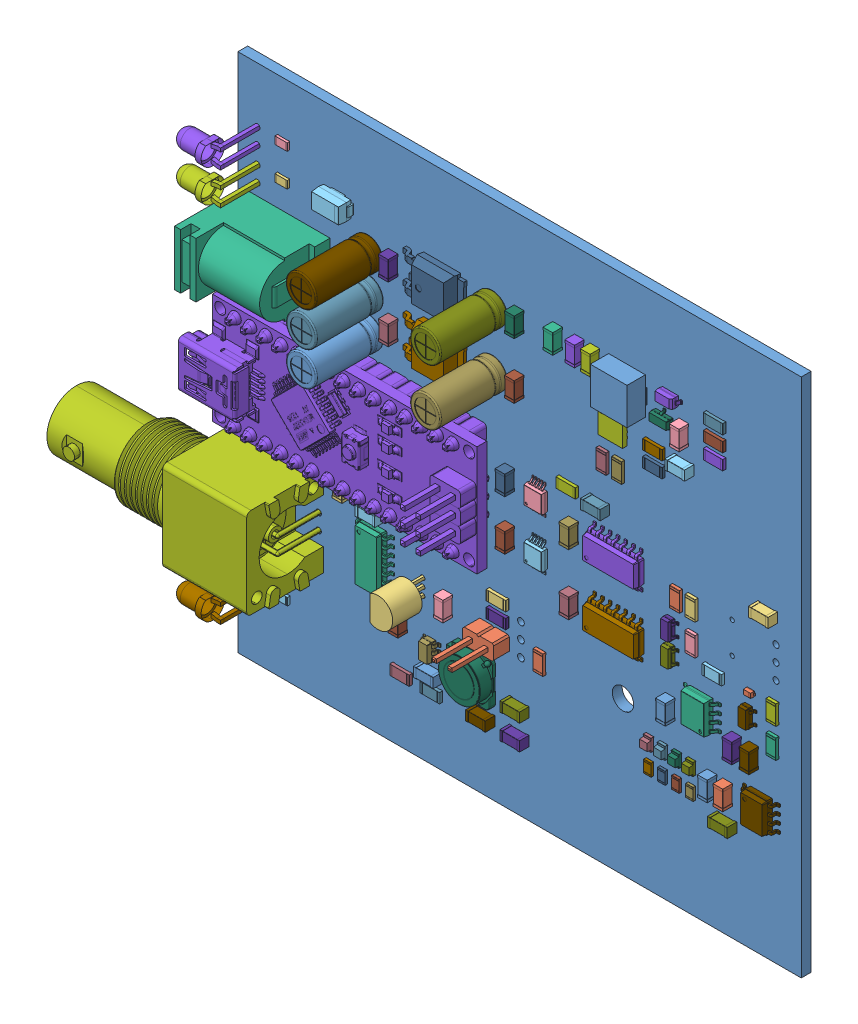
SolidWorks assembly PCBA_cut, configuration Domyślna. Lengths in mm.
Overall size (111.73 85 18.8).
103 component instances, 99 part files, 0 mates.
Components (placement in the parent):
- PCBA.step-1: PCBA.step [Domyślna] at origin size (111.73 89 18.8)
  - Board_Geoms_e78a.step-1: Board_Geoms_e78a.step [Domyślna] at origin size (92 89 1.6)
    - Pcb_e78a.step-1: Pcb_e78a.step [Domyślna] at (-104.194 136.428 0) size (92 89 1.6)
    - PCB_Sketch_e78a.step-1: PCB_Sketch_e78a.step [Domyślna] at origin (suppressed, hidden)
  - Step_Models_e78a.step-1: Step_Models_e78a.step [Domyślna] at origin size (108.33 68.14 18.8)
    - Top_e78a.step-1: Top_e78a.step [Domyślna] at origin size (108.33 68.14 18.8)
      - R28_R_1206_3216Metric_60135E3C.step-1: R28_R_1206_3216Metric_60135E3C.step [Domyślna] at (49.53 8.636 0) x (0 1 0) z (0 0 1) size (3.2 1.6 0.55)
      - R27_R_0805_2012Metric_5F3C1C00.step-1: R27_R_0805_2012Metric_5F3C1C00.step [Domyślna] at (7.493 55.626 0) size (2 1.2 0.45)
      - R26_R_0805_2012Metric_5F3C1C30.step-1: R26_R_0805_2012Metric_5F3C1C30.step [Domyślna] at (7.493 60.96 0) size (2 1.2 0.45)
      - R25_R_0805_2012Metric_5F3C1E7C.step-1: R25_R_0805_2012Metric_5F3C1E7C.step [Domyślna] at (7.5415 -3.302 0) size (2 1.2 0.45)
      - R24_R_0805_2012Metric_60130AB3.step-1: R24_R_0805_2012Metric_60130AB3.step [Domyślna] at (7.493 2.032 0) size (2 1.2 0.45)
      - D12_LED_D3.0mm_Horizontal_O1.27mm_Z6.0mm_5F3C2200.step-1: D12_LED_D3.0mm_Horizontal_O1.27mm_Z6.0mm_5F3C2200.step [Domyślna] at (3.175 55.626 0) x (0 -1 0) z (0 0 1) size (3.48 6.88 9.91)
      - D11_LED_D3.0mm_Horizontal_O1.27mm_Z6.0mm_5F3C2185.step-1: D11_LED_D3.0mm_Horizontal_O1.27mm_Z6.0mm_5F3C2185.step [Domyślna] at (3.175 60.96 0) x (0 -1 0) z (0 0 1) size (3.48 6.88 9.91)
      - D10_LED_D3.0mm_Horizontal_O1.27mm_Z6.0mm_5F3C56BC.step-1: D10_LED_D3.0mm_Horizontal_O1.27mm_Z6.0mm_5F3C56BC.step [Domyślna] at (3.175 -3.302 0) x (0 -1 0) z (0 0 1) size (3.48 6.88 9.91)
      - D9_LED_D3.0mm_Horizontal_O1.27mm_Z6.0mm_5F3C1D9F.step-1: D9_LED_D3.0mm_Horizontal_O1.27mm_Z6.0mm_5F3C1D9F.step [Domyślna] at (3.175 2.032 0) x (0 -1 0) z (0 0 1) size (3.48 6.88 9.91)
      - C31_C_1206_3216Metric_5F0E55A1.step-1: C31_C_1206_3216Metric_5F0E55A1.step [Domyślna] at (26.924 3.302 0) x (0 -1 0) z (0 0 1) size (3.2 1.6 1.6)
      - IC12_SOT_23_6_5F31C27B.step-1: IC12_SOT_23_6_5F31C27B.step [Domyślna] at (31.75 1.651 0) x (-1 0 0) z (0 0 1) size (2.8 2.9 1.55)
      - R23_R_1206_3216Metric_5F31C265.step-1: R23_R_1206_3216Metric_5F31C265.step [Domyślna] at (26.924 -4.445 0) size (3.2 1.6 0.55)
      - R22_R_1206_3216Metric_5F31DD4A.step-1: R22_R_1206_3216Metric_5F31DD4A.step [Domyślna] at (31.877 -4.445 0) x (-1 0 0) z (0 0 1) size (3.2 1.6 0.55)
      - L2_Sf_fd_sp_5F31CDB4[2].step-1: L2_Sf_fd_sp_5F31CDB4[2].step [Domyślna] at (38.608 1.651 0.0508) size (7 7 2.5)
      - C36_C_1206_3216Metric_5F31B990.step-1: C36_C_1206_3216Metric_5F31B990.step [Domyślna] at (45.974 0.381 0) size (3.2 1.6 1.6)
      - C35_C_1206_3216Metric_5F31B97F.step-1: C35_C_1206_3216Metric_5F31B97F.step [Domyślna] at (45.974 -3.683 0) size (3.2 1.6 1.6)
      - C34_C_1206_3216Metric_5F31B96E.step-1: C34_C_1206_3216Metric_5F31B96E.step [Domyślna] at (40.386 -3.683 0) x (-1 0 0) z (0 0 1) size (3.2 1.6 1.6)
      - C33_C_1206_3216Metric_5F31B95D.step-1: C33_C_1206_3216Metric_5F31B95D.step [Domyślna] at (31.877 -1.778 0) x (-1 0 0) z (0 0 1) size (3.2 1.6 1.6)
      - C32_C_1206_3216Metric_5F2DB7B1.step-1: C32_C_1206_3216Metric_5F2DB7B1.step [Domyślna] at (5.334 24.384 0) x (-1 0 0) z (0 0 1) size (3.2 1.6 1.6)
      - R21_R_1206_3216Metric_5F2CE966.step-1: R21_R_1206_3216Metric_5F2CE966.step [Domyślna] at (42.672 13.97 0) size (3.2 1.6 0.55)
      - IC8_DS1124U-25+_5F0C9A39.step-1: IC8_DS1124U-25+_5F0C9A39.step [Domyślna] at (49.222 31.78 0) x (0 1 0) z (0 0 1) size (4.9 3 1.1)
      - IC7_DS1124U-25+_5F0C50CD.step-1: IC7_DS1124U-25+_5F0C50CD.step [Domyślna] at (49.222 23.652 0) x (0 1 0) z (0 0 1) size (4.9 3 1.1)
      - IC2_TLV3501AIDR_5F0DC31C.step-1: IC2_TLV3501AIDR_5F0DC31C.step [Domyślna] at (75.944 15.19 0) x (-1 0 0) z (0 0 1) size (6 4.9 1.75)
      - IC1_MAX1932ETC+_5F0DC301.step-1: IC1_MAX1932ETC+_5F0DC301.step [Domyślna] at (61.614 48.076 0) size (4.1 4.1 0.8)
      - D1_BAT46W-E3-08_5F0B6668.step-1: D1_BAT46W-E3-08_5F0B6668.step [Domyślna] at (70.758 56.712 0) x (-1 0 0) z (0 0 1) size (3.7 1.55 1.35)
      - R20_R_0805_2012Metric_5F2C1AB9.step-1: R20_R_0805_2012Metric_5F2C1AB9.step [Domyślna] at (67.31 2.54 0) x (0 -1 0) z (0 0 1) size (2 1.2 0.45)
      - R19_R_0805_2012Metric_5F2C1B19.step-1: R19_R_0805_2012Metric_5F2C1B19.step [Domyślna] at (69.596 2.54 0) x (0 -1 0) z (0 0 1) size (2 1.2 0.45)
      - R16_R_0805_2012Metric_5F2C1B49.step-1: R16_R_0805_2012Metric_5F2C1B49.step [Domyślna] at (71.882 2.54 0) x (0 -1 0) z (0 0 1) size (2 1.2 0.45)
      - R13_R_0805_2012Metric_5F2C1AE9.step-1: R13_R_0805_2012Metric_5F2C1AE9.step [Domyślna] at (74.168 2.54 0) x (0 -1 0) z (0 0 1) size (2 1.2 0.45)
      - D8_LED_0805_2012Metric_5F2C1BB1.step-1: D8_LED_0805_2012Metric_5F2C1BB1.step [Domyślna] at (67.31 6.096 0) x (0 1 0) z (0 0 1) size (2 1.25 1.1)
      - D7_LED_0805_2012Metric_5F2C1BE7.step-1: D7_LED_0805_2012Metric_5F2C1BE7.step [Domyślna] at (69.596 6.096 0) x (0 1 0) z (0 0 1) size (2 1.25 1.1)
      - D6_LED_0805_2012Metric_5F2C1B7B.step-1: D6_LED_0805_2012Metric_5F2C1B7B.step [Domyślna] at (71.882 6.096 0) x (0 1 0) z (0 0 1) size (2 1.25 1.1)
      - D5_LED_0805_2012Metric_5F2B9F6D.step-1: D5_LED_0805_2012Metric_5F2B9F6D.step [Domyślna] at (74.168 6.096 0) x (0 1 0) z (0 0 1) size (2 1.25 1.1)
      - R10_R_1206_3216Metric_5F2BA4CF.step-1: R10_R_1206_3216Metric_5F2BA4CF.step [Domyślna] at (42.672 11.43 0) size (3.2 1.6 0.55)
      - IC5_SOIC_8_39x49mm_P127mm_5F2C782A.step-1: IC5_SOIC_8_39x49mm_P127mm_5F2C782A.step [Domyślna] at (85.598 5.788 0) size (6 4.9 1.75)
      - C30_C_Radial_D50mm_H110mm_P200mm_5F0E5590.step-1: C30_C_Radial_D50mm_H110mm_P200mm_5F0E5590.step [Domyślna] at (21.336 42.164 0) x (0 -1 0) z (0 0 1) size (6.29 6.83 13)
      - J2_PinHeader_1x02_P254mm_Vertical_6016EDB8.step-1: J2_PinHeader_1x02_P254mm_Vertical_6016EDB8.step [Domyślna] at (40.513 8.382 0) x (0 1 0) z (0 0 1) size (2.54 5.08 11.54)
      - IC11_TO-92_Inline_Narrow_5F0E2760.step-1: IC11_TO-92_Inline_Narrow_5F0E2760.step [Domyślna] at (30.172 10.698 0) x (0 -1 0) z (0 0 1) size (4.83 3.75 9.8)
      - C29_C_1206_3216Metric_5F0F3A25.step-1: C29_C_1206_3216Metric_5F0F3A25.step [Domyślna] at (34.29 9.144 0) x (0 -1 0) z (0 0 1) size (3.2 1.6 1.6)
      - C28_C_1206_3216Metric_5F0EE626.step-1: C28_C_1206_3216Metric_5F0EE626.step [Domyślna] at (22.352 16.256 0) x (-1 0 0) z (0 0 1) size (3.2 1.6 1.6)
      - IC10_SOIC_14_39x87mm_P127mm_5F0D8E3B.step-1: IC10_SOIC_14_39x87mm_P127mm_5F0D8E3B.step [Domyślna] at (22.617 10.19 0) size (6 8.7 1.75)
      - R9_R_1206_3216Metric_5F0C53DD.step-1: R9_R_1206_3216Metric_5F0C53DD.step [Domyślna] at (54.048 35.59 0) size (3.2 1.6 0.55)
      - IC9_SOIC_14_39x87mm_P127mm_5F0C510A.step-1: IC9_SOIC_14_39x87mm_P127mm_5F0C510A.step [Domyślna] at (62.176 29.748 0) x (0 1 0) z (0 0 1) size (6 8.7 1.75)
      - IC6_SOIC_14_39x87mm_P127mm_5F0C50B0.step-1: IC6_SOIC_14_39x87mm_P127mm_5F0C50B0.step [Domyślna] at (62.176 19.842 0) x (0 1 0) z (0 0 1) size (6 8.7 1.75)
      - C27_C_1206_3216Metric_5F0C4ED7.step-1: C27_C_1206_3216Metric_5F0C4ED7.step [Domyślna] at (44.396 32.034 0) x (0 -1 0) z (0 0 1) size (3.2 1.6 1.6)
      - C26_C_1206_3216Metric_5F0C4EC6.step-1: C26_C_1206_3216Metric_5F0C4EC6.step [Domyślna] at (44.396 23.906 0) x (0 -1 0) z (0 0 1) size (3.2 1.6 1.6)
      - C25_C_1206_3216Metric_5F0C4EB5.step-1: C25_C_1206_3216Metric_5F0C4EB5.step [Domyślna] at (54.81 29.748 0) x (0 -1 0) z (0 0 1) size (3.2 1.6 1.6)
      - C24_C_1206_3216Metric_5F0C4EA4.step-1: C24_C_1206_3216Metric_5F0C4EA4.step [Domyślna] at (54.81 19.842 0) x (0 -1 0) z (0 0 1) size (3.2 1.6 1.6)
      - C23_C_1206_3216Metric_5F0C4E93.step-1: C23_C_1206_3216Metric_5F0C4E93.step [Domyślna] at (59.128 35.59 0) size (3.2 1.6 1.6)
      - R4_R_1206_3216Metric_5F0BCC0F.step-1: R4_R_1206_3216Metric_5F0BCC0F.step [Domyślna] at (33.474 24.414 0) size (3.2 1.6 0.55)
      - C22_C_1206_3216Metric_5F2C77F1.step-1: C22_C_1206_3216Metric_5F2C77F1.step [Domyślna] at (79.886 1.016 0) x (-1 0 0) z (0 0 1) size (3.2 1.6 1.6)
      - C21_C_1206_3216Metric_5F0BC811.step-1: C21_C_1206_3216Metric_5F0BC811.step [Domyślna] at (81.452 12.646 0) x (0 -1 0) z (0 0 1) size (3.2 1.6 1.6)
      - C20_C_1206_3216Metric_5F0BC800.step-1: C20_C_1206_3216Metric_5F0BC800.step [Domyślna] at (84.246 12.646 0) x (0 -1 0) z (0 0 1) size (3.2 1.6 1.6)
      - C19_C_1206_3216Metric_5F2C7791.step-1: C19_C_1206_3216Metric_5F2C7791.step [Domyślna] at (77.44 5.28 0) x (0 -1 0) z (0 0 1) size (3.2 1.6 1.6)
      - C18_C_1206_3216Metric_5F2C77C1.step-1: C18_C_1206_3216Metric_5F2C77C1.step [Domyślna] at (79.98 5.28 0) x (0 -1 0) z (0 0 1) size (3.2 1.6 1.6)
      - C17_C_1206_3216Metric_5F0BB606.step-1: C17_C_1206_3216Metric_5F0BB606.step [Domyślna] at (17.78 17.78 0) x (0 -1 0) z (0 0 1) size (3.2 1.6 1.6)
      - C16_C_1206_3216Metric_5F0BBC4D.step-1: C16_C_1206_3216Metric_5F0BBC4D.step [Domyślna] at (33.728 18.572 0) size (3.2 1.6 1.6)
      - D4_D_SMA_5F0B762E.step-1: D4_D_SMA_5F0B762E.step [Domyślna] at (16.456 57.18 0) x (-1 0 0) z (0 0 1) size (5 2.7 2.22)
      - J4_CUI_DEVICES_PJ-102AH_5F0EDE56.step-1: J4_CUI_DEVICES_PJ-102AH_5F0EDE56.step [Domyślna] at (0.7334 46.736 6.5786) x (-1 0 0) z (0 1 0) size (14.4 14.5 9.4)
      - J3_73100-0131_5F0BBBC4.step-1: J3_73100-0131_5F0BBBC4.step [Domyślna] at (-2.4892 11.43 6.6548) x (0 -1 0) z (-1 0 0) size (14.76 18.23 35.18)
      - A1_arduino_nano_5F2D0076.step-1: A1_arduino_nano_5F2D0076.step [Domyślna] at (39.824 36.86 3) x (-1 0 0) z (0 1 0) size (45 18.6 18)
      - IC4_TO_252_2_5F0B63C8.step-1: IC4_TO_252_2_5F0B63C8.step [Domyślna] at (32.458 44.48 0) size (9.9 6.5 2.32)
      - IC3_TO_252_2_5F0B6491.step-1: IC3_TO_252_2_5F0B6491.step [Domyślna] at (32.458 53.624 0) size (9.9 6.5 2.32)
      - C15_C_1206_3216Metric_5F0B641E.step-1: C15_C_1206_3216Metric_5F0B641E.step [Domyślna] at (45.92 46.004 0) x (0 1 0) z (0 0 1) size (3.2 1.6 1.6)
      - C14_C_Radial_D50mm_H110mm_P200mm_5F0B62A3.step-1: C14_C_Radial_D50mm_H110mm_P200mm_5F0B62A3.step [Domyślna] at (41.602 44.48 0) x (0 1 0) z (0 0 1) size (6.29 6.83 13)
      - C13_C_1206_3216Metric_5F0B644E.step-1: C13_C_1206_3216Metric_5F0B644E.step [Domyślna] at (25.346 43.718 0) x (0 1 0) z (0 0 1) size (3.2 1.6 1.6)
      - C12_C_Radial_D50mm_H110mm_P200mm_5F0B62BE.step-1: C12_C_Radial_D50mm_H110mm_P200mm_5F0B62BE.step [Domyślna] at (21.336 45.72 0) x (0 1 0) z (0 0 1) size (6.29 6.83 13)
      - C11_C_1206_3216Metric_5F0B62E0.step-1: C11_C_1206_3216Metric_5F0B62E0.step [Domyślna] at (45.92 55.148 0) x (0 1 0) z (0 0 1) size (3.2 1.6 1.6)
      - C10_C_Radial_D50mm_H110mm_P200mm_5F0B6309.step-1: C10_C_Radial_D50mm_H110mm_P200mm_5F0B6309.step [Domyślna] at (41.602 53.624 0) x (0 1 0) z (0 0 1) size (6.29 6.83 13)
      - C9_C_1206_3216Metric_5F0B6385.step-1: C9_C_1206_3216Metric_5F0B6385.step [Domyślna] at (25.346 52.862 0) x (0 1 0) z (0 0 1) size (3.2 1.6 1.6)
      - C8_C_Radial_D50mm_H110mm_P200mm_5F0B6324.step-1: C8_C_Radial_D50mm_H110mm_P200mm_5F0B6324.step [Domyślna] at (21.282 51.338 0) x (0 1 0) z (0 0 1) size (6.29 6.83 13)
      - C7_C_1206_3216Metric_5F0C274F.step-1: C7_C_1206_3216Metric_5F0C274F.step [Domyślna] at (70.61 12.7 0) x (0 -1 0) z (0 0 1) size (3.2 1.6 1.6)
      - R18_R_1206_3216Metric_5F0A53A7.step-1: R18_R_1206_3216Metric_5F0A53A7.step [Domyślna] at (71.828 28.732 0) x (0 1 0) z (0 0 1) size (3.2 1.6 0.55)
      - R17_R_1206_3216Metric_5F0A5396.step-1: R17_R_1206_3216Metric_5F0A5396.step [Domyślna] at (74.368 28.732 0) x (0 1 0) z (0 0 1) size (3.2 1.6 0.55)
      - R15_R_1206_3216Metric_5F0A5385.step-1: R15_R_1206_3216Metric_5F0A5385.step [Domyślna] at (74.368 23.652 0) x (0 -1 0) z (0 0 1) size (3.2 1.6 0.55)
      - R14_R_1206_3216Metric_5F0A5374.step-1: R14_R_1206_3216Metric_5F0A5374.step [Domyślna] at (77.924 21.112 0) size (3.2 1.6 0.55)
      - R12_R_1206_3216Metric_5F0A5363.step-1: R12_R_1206_3216Metric_5F0A5363.step [Domyślna] at (87.576 15.778 0) x (0 -1 0) z (0 0 1) size (3.2 1.6 0.55)
      - R11_R_1206_3216Metric_5F0D1442.step-1: R11_R_1206_3216Metric_5F0D1442.step [Domyślna] at (87.576 20.604 0) x (0 -1 0) z (0 0 1) size (3.2 1.6 0.55)
      - R8_R_1206_3216Metric_5F0B69A0.step-1: R8_R_1206_3216Metric_5F0B69A0.step [Domyślna] at (78.124 51.632 0) size (3.2 1.6 0.55)
      - R7_R_1206_3216Metric_5F0B6970.step-1: R7_R_1206_3216Metric_5F0B6970.step [Domyślna] at (68.218 48.076 0) size (3.2 1.6 0.55)
      - R6_R_1206_3216Metric_5F0B680B.step-1: R6_R_1206_3216Metric_5F0B680B.step [Domyślna] at (68.218 45.536 0) x (-1 0 0) z (0 0 1) size (3.2 1.6 0.55)
      - R5_R_1206_3216Metric_5F0B67AB.step-1: R5_R_1206_3216Metric_5F0B67AB.step [Domyślna] at (78.124 54.172 0) x (-1 0 0) z (0 0 1) size (3.2 1.6 0.55)
      - R3_R_1206_3216Metric_5F0B6940.step-1: R3_R_1206_3216Metric_5F0B6940.step [Domyślna] at (62.376 42.234 0) x (0 1 0) z (0 0 1) size (3.2 1.6 0.55)
      - R2_R_1206_3216Metric_5F0B6910.step-1: R2_R_1206_3216Metric_5F0B6910.step [Domyślna] at (59.836 42.234 0) x (0 -1 0) z (0 0 1) size (3.2 1.6 0.55)
      - R1_R_1206_3216Metric_5F0B68E0.step-1: R1_R_1206_3216Metric_5F0B68E0.step [Domyślna] at (78.124 56.712 0) size (3.2 1.6 0.55)
      - Q4_SOT_23_5F0B68A8.step-1: Q4_SOT_23_5F0B68A8.step [Domyślna] at (69.742 53.156 0) x (0 1 0) z (0 0 1) size (2.5 3 1.2)
      - Q3_SOT_23_5F0B91D4.step-1: Q3_SOT_23_5F0B91D4.step [Domyślna] at (70.812 20.35 0) x (-1 0 0) z (0 0 1) size (2.5 3 1.2)
      - Q2_SOT_23_5F0B9198.step-1: Q2_SOT_23_5F0B9198.step [Domyślna] at (70.812 24.16 0) x (-1 0 0) z (0 0 1) size (2.5 3 1.2)
      - Q1_SOT_23_5F0A528B.step-1: Q1_SOT_23_5F0A528B.step [Domyślna] at (83.512 18.064 0) x (-1 0 0) z (0 0 1) size (2.5 3 1.2)
      - L1_#A921CY-101M=P3_5F0B67DB.step-1: L1_#A921CY-101M=P3_5F0B67DB.step [Domyślna] at (63.646 54.68 0) size (6.4 6 3.1)
      - D2_D_SOD_523_5F0A520A.step-1: D2_D_SOD_523_5F0A520A.step [Domyślna] at (83.766 21.366 0) x (-1 0 0) z (0 0 1) size (1.6 0.8 0.63)
      - C6_C_1206_3216Metric_5F0A72A1.step-1: C6_C_1206_3216Metric_5F0A72A1.step [Domyślna] at (86.56 34.066 0) size (3.2 1.6 1.6)
      - C5_C_1206_3216Metric_5F0A51C2.step-1: C5_C_1206_3216Metric_5F0A51C2.step [Domyślna] at (72.844 52.608 0) x (0 1 0) z (0 0 1) size (3.2 1.6 1.6)
      - C4_C_1206_3216Metric_5F0B66CA.step-1: C4_C_1206_3216Metric_5F0B66CA.step [Domyślna] at (72.914 48.076 0) x (-1 0 0) z (0 0 1) size (3.2 1.6 1.6)
      - C3_C_1206_3216Metric_5F0B66FA.step-1: C3_C_1206_3216Metric_5F0B66FA.step [Domyślna] at (52.216 55.95 0) x (0 1 0) z (0 0 1) size (3.2 1.6 1.6)
      - C2_C_1206_3216Metric_5F0B669A.step-1: C2_C_1206_3216Metric_5F0B669A.step [Domyślna] at (58.312 55.95 0) x (0 1 0) z (0 0 1) size (3.2 1.6 1.6)
      - C1_C_1206_3216Metric_5F0B677B.step-1: C1_C_1206_3216Metric_5F0B677B.step [Domyślna] at (55.772 55.95 0) x (0 1 0) z (0 0 1) size (3.2 1.6 1.6)
